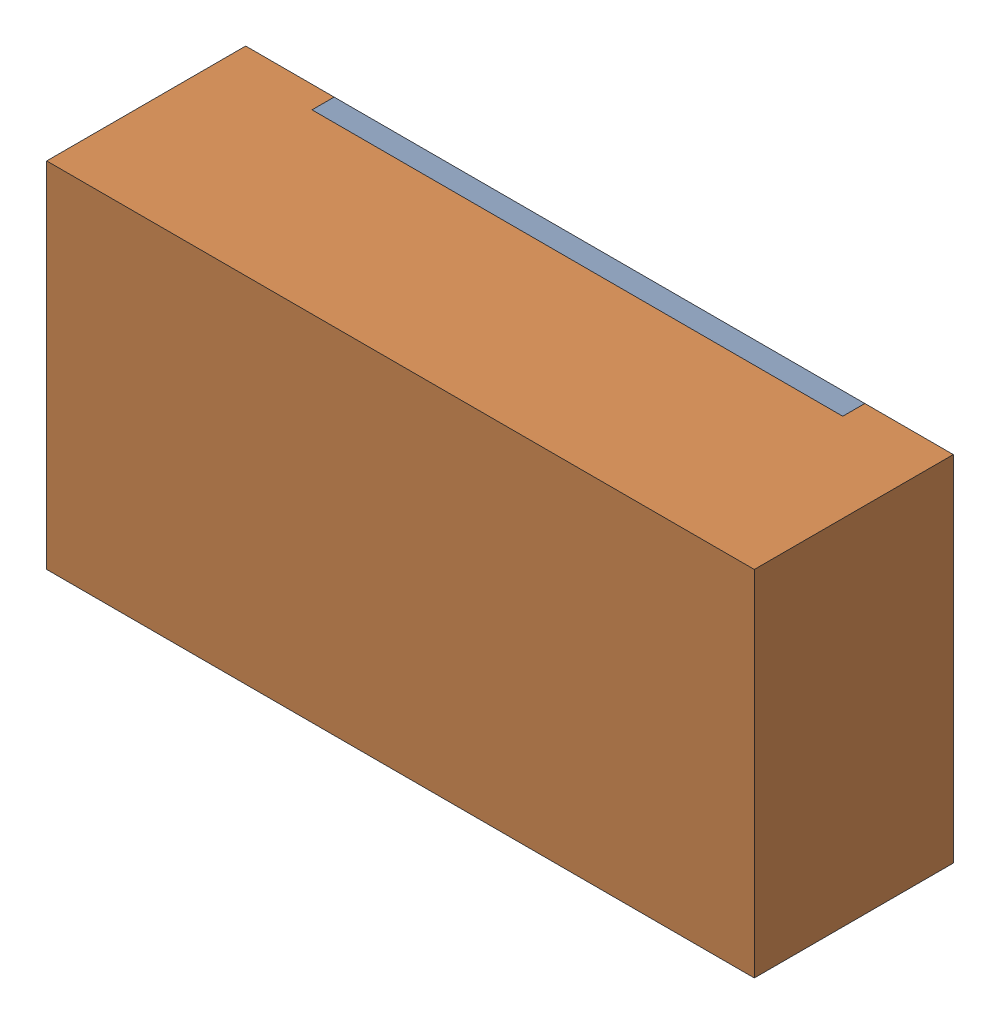
SolidWorks assembly R6, configuration 默认. Lengths in mm.
Overall size (1.6 0.8 0.45).
3 component instances, 2 part files, 0 mates.
Components (placement in the parent):
- R6-subassembly-1-1: R6-subassembly-1 [默认] at (3.6831 15.4939 -1.6914) x (1 0 0) z (0 0 -1) size (1.6 0.8 0.45)
  - R0603-1: R0603 [默认] at origin size (1.2 0.8 0.05)
  - R0603-1-1: R0603-1 [默认] at origin size (1.6 0.8 0.45)
